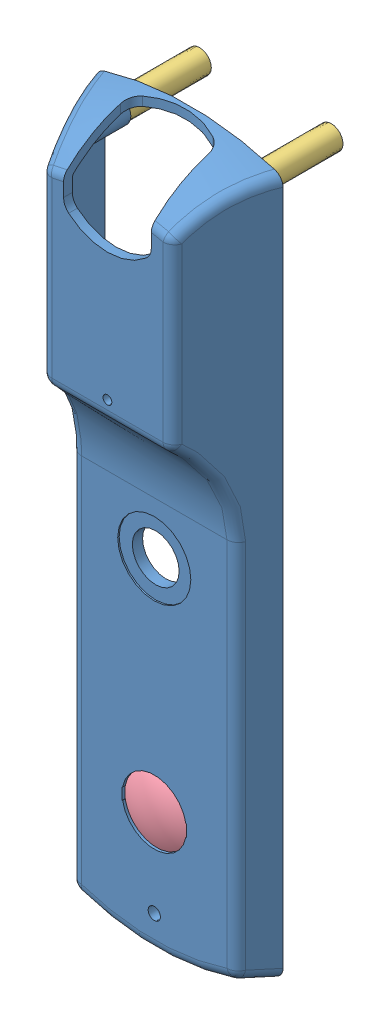
SolidWorks assembly Assemblage a1, configuration Défaut. Lengths in mm.
Overall size (69.84 249.51 54.23).
13 component instances, 7 part files, 18 mates.
Components (placement in the parent):
- piece a1-1: piece a1 [Défaut] at (2.8343 16.0422 0) size (69.84 249.51 28.23)
- pièce a9-4: pièce a9 [Défaut] at (-3.5296 -52.5939 9) size (3 3 2)
- pièce a9-5: pièce a9 [Défaut] at (0.505 -67.6512 9) x (-0.5 0.866025 0) z (0 0 1) size (3 3 2)
- pièce a9-6: pièce a9 [Défaut] at (11.5277 -56.6285 9) x (-0.5 -0.866025 0) z (0 0 1) size (3 3 2)
- pièce a8-1: pièce a8 [Défaut] at (25.3343 133.0422 8) x (0 0 -1) z (1 0 0) size (34 8 8)
- pièce a8-2: pièce a8 [Défaut] at (-19.6657 133.0422 8) x (0 0 -1) z (1 0 0) size (34 8 8)
- pièce a27-1: pièce a27 [Défaut] at (2.8343 -58.9578 11) size (22 22 2.5)
- pièce a8-3: pièce a8 [Défaut] at (2.8343 -88.9578 8) x (0 0 -1) z (1 0 0) size (34 8 8)
- pièce a26-1: pièce a26 [Défaut] at (2.8343 71.0422 17) size (45 18 2)
- piece a20-1: piece a20 [ISO 7045 - M3 x 8 - Z --- 8N] at (-15.6657 104.0422 16.1) x (0 0 1) z (-1 0 0) size (10.35 5.6 5.6)
- piece a20-2: piece a20 [ISO 7045 - M3 x 8 - Z --- 8N] at (21.3343 104.0422 16.1) x (0 0 1) z (-1 0 0) size (10.35 5.6 5.6)
- piece a21-1: piece a21 [ISO 7045 - M3 x 6 - Z --- 6N] at (-15.6657 71.0422 14.6) x (0 0 1) z (-1 0 0) size (8.35 5.6 5.6)
- piece a21-2: piece a21 [ISO 7045 - M3 x 6 - Z --- 6N] at (21.3343 71.0422 14.6) x (0 0 1) z (-1 0 0) size (8.35 5.6 5.6)
Mates (geometry in assembly coordinates):
- Coaxiale9: concentric anti-aligned: cylinder of piece a1-1 through (-3.5296 -52.5939 -0.001) axis (0 0 1) radius 1.5; cylinder of pièce a9-4 through (-3.5296 -52.5939 11) axis (0 0 -1) radius 1.5
- Coïncidente16: coincident aligned: plane of piece a1-1 through (2.8343 -58.9578 11) normal (0 0 1); plane of pièce a9-4 through (-3.5296 -52.5939 11) normal (0 0 1)
- Coaxiale12: concentric aligned: cylinder of piece a1-1 through (25.3343 133.0422 0) axis (0 0 -1) radius 2; cylinder of pièce a8-1 through (25.3343 133.0422 -26) axis (0 0 -1) radius 2.5
- Coïncidente20: coincident anti-aligned: plane of piece a1-1 through (25.3343 133.0422 2) normal (0 0 -1); plane of pièce a8-1 through (25.3343 135.5422 2) normal (0 0 1)
- Coaxiale13: concentric aligned: cylinder of piece a1-1 through (-19.6657 133.0422 2) axis (0 0 -1) radius 2; cylinder of pièce a8-2 through (-19.6657 133.0422 -26) axis (0 0 -1) radius 2.5
- Coïncidente21: coincident anti-aligned: plane of piece a1-1 through (-19.6657 133.0422 2) normal (0 0 -1); plane of pièce a8-2 through (-19.6657 135.5422 2) normal (0 0 1)
- Coïncidente26: coincident anti-aligned: plane of piece a1-1 through (2.8343 -58.9578 11) normal (0 0 1); plane of pièce a27-1 through (2.8343 -58.9578 11) normal (0 0 -1)
- Coaxiale15: concentric aligned: circle of pièce a27-1; cylinder of piece a1-1 through (2.8343 -58.9578 -0.001) axis (0 0 1) radius 6.5
- Coaxiale16: concentric aligned: cylinder of piece a1-1 through (2.8343 -88.9578 2) axis (0 0 -1) radius 2.1; cylinder of pièce a8-3 through (2.8343 -88.9578 -26) axis (0 0 -1) radius 2.5
- Coïncidente27: coincident anti-aligned: plane of piece a1-1 through (2.8343 -88.9578 2) normal (0 0 -1); plane of pièce a8-3 through (2.8343 -86.4578 2) normal (0 0 1)
- Coïncidente43: coincident anti-aligned: plane of piece a1-1 through (-15.6657 71.0422 19) normal (0 0 -1); plane of pièce a26-1 through (-19.6657 62.0422 19) normal (0 0 1)
- Coaxiale23: concentric aligned: cylinder of piece a1-1 through (2.8343 71.0422 -0.001) axis (0 0 1) radius 1.5; cylinder of pièce a26-1 through (2.8343 71.0422 16.999) axis (0 0 1) radius 3.5
- Coaxiale24: concentric aligned: cylinder of piece a1-1 through (-15.6657 104.0422 19) axis (0 0 -1) radius 1; cylinder of piece a20-1 through (-15.6657 104.0422 -9.3) axis (0 0 -1) radius 1.5
- Coaxiale25: concentric aligned: cylinder of piece a1-1 through (21.3343 104.0422 19) axis (0 0 -1) radius 1; cylinder of piece a20-2 through (21.3343 104.0422 -9.3) axis (0 0 -1) radius 1.5
- Coaxiale26: concentric aligned: cylinder of piece a1-1 through (21.3343 71.0422 19) axis (0 0 -1) radius 1; cylinder of piece a21-2 through (21.3343 71.0422 -10.8) axis (0 0 -1) radius 1.5
- Coïncidente51: coincident anti-aligned: plane of pièce a26-1 through (-19.6657 62.0422 17) normal (0 0 -1); plane of piece a21-2 through (21.3343 72.5422 17) normal (0 0 1)
- Coaxiale27: concentric aligned: cylinder of piece a1-1 through (-15.6657 71.0422 19) axis (0 0 -1) radius 1; cylinder of piece a21-1 through (-15.6657 71.0422 -10.8) axis (0 0 -1) radius 1.5
- Coïncidente52: coincident anti-aligned: plane of pièce a26-1 through (-19.6657 62.0422 17) normal (0 0 -1); plane of piece a21-1 through (-15.6657 72.5422 17) normal (0 0 1)
